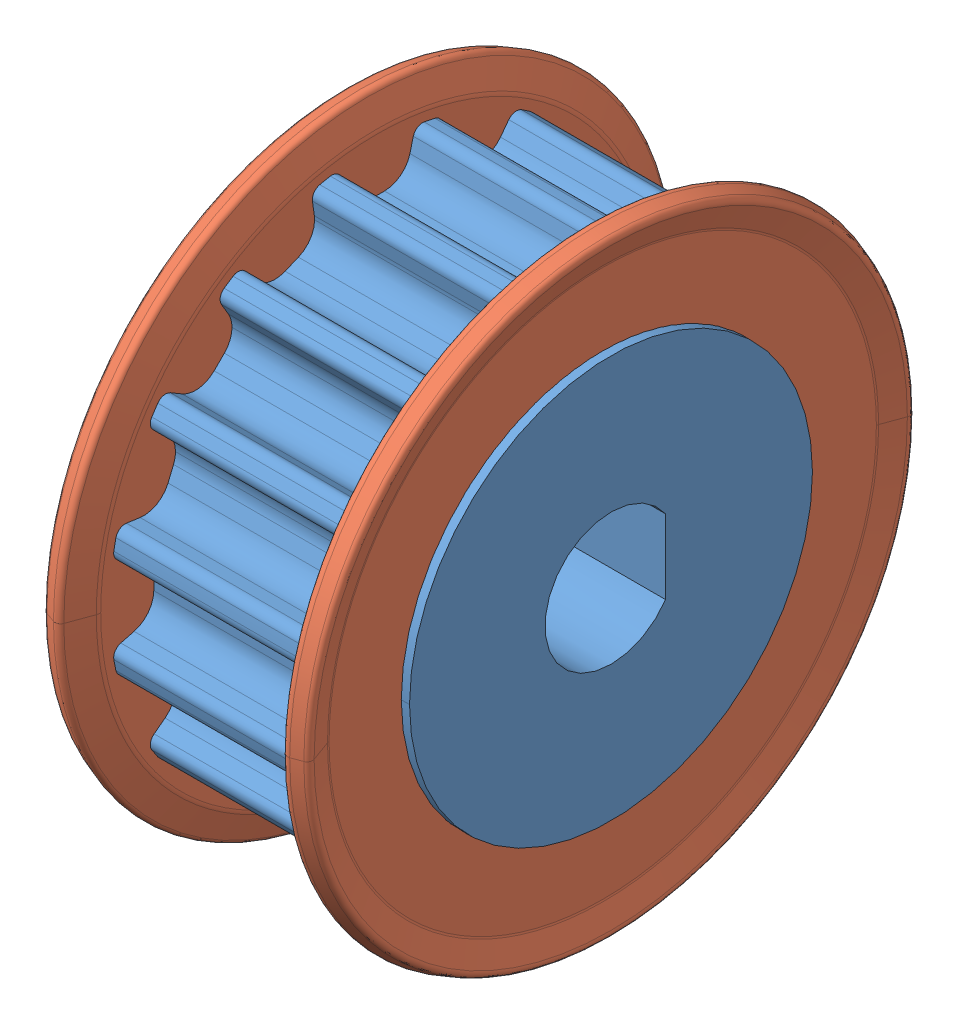
SolidWorks assembly 3414-1006-0016 assembly, configuration Default. Lengths in mm.
Overall size (12.01 27.98 27.98).
5 component instances, 3 part files, 0 mates.
Components (placement in the parent):
- 3414-1006-0016 assembly.STEP-1: 3414-1006-0016 assembly.STEP [Default] at origin size (12.01 27.98 27.98)
  - 3414-1006-0016 body.STEP-1: 3414-1006-0016 body.STEP [Default] at (-62.7232 -4.1348 4.7756) size (12 23.97 23.97)
  - 3414-4008-0016 ring.STEP-1: 3414-4008-0016 ring.STEP [Default] at (-50.8429 9.3571 23.0035) x (0 -1 0) z (0 0 1) size (27.98 1.38 27.98)
  - 3414-4008-0016 ring.STEP-2: 3414-4008-0016 ring.STEP [Default] at (-60.0929 9.3571 23.0035) x (0 -1 0) z (0 0 -1) size (27.98 1.38 27.98)
  - 2806-0005-0006_91390A118.STEP-1: 2806-0005-0006_91390A118.STEP [Default] at (-55.4679 9.3571 17.1119) x (-0.607877 0.794031 0) z (0 0 -1) size (5.01 5.01 6.01)
